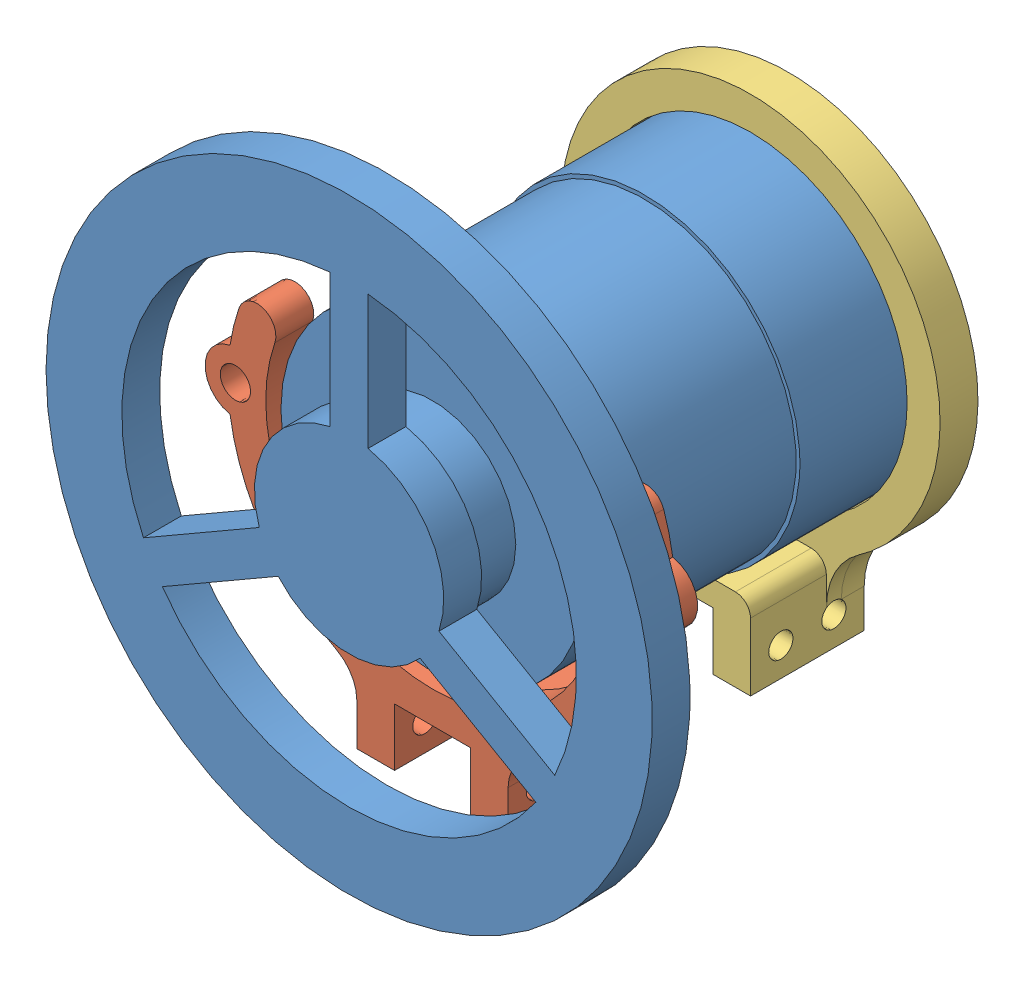
SolidWorks assembly flywheel, configuration 默认. Lengths in mm.
Overall size (80 80 59).
3 component instances, 3 part files, 9 mates.
Components (placement in the parent):
- flywheel-1: flywheel [默认] at origin size (80 80 59)
- flywheel_holder1-1: flywheel_holder1 [默认] at (0 0 48) x (1 0 0) z (0 1 0) size (60 15 44.31)
- flywheel_holder2-1: flywheel_holder2 [默认] at (0 0 1) x (-1 0 0) z (0 1 0) size (50 15 58.81)
Mates (geometry in assembly coordinates):
- 同心1: concentric aligned: circle of flywheel-1; circle of flywheel_holder1-1
- 同心2: concentric aligned: circle of flywheel-1; circle of flywheel_holder2-1
- 重合3: coincident aligned: plane of flywheel-1 through (0 -2.9898 0) normal (0 1 0); plane of flywheel_holder1-1 through (0 -2.9898 48) normal (0 1 0)
- 重合4: coincident aligned: plane of flywheel-1 through (0 -2.9898 0) normal (0 1 0); plane of flywheel_holder2-1 through (0 -2.9898 1) normal (0 1 0)
- 重合5: coincident aligned: plane of flywheel-1 through (0 -2.9898 48) normal (0 0 1); plane of flywheel_holder1-1 through (-11.5785 1.0102 48) normal (0 0 1)
- 距离1: distance = 1 mm aligned: plane of flywheel-1 through (0 0 0) normal (0 0 -1); plane of flywheel_holder2-1 through (0 0 1) normal (0 0 -1)
- 重合6: coincident aligned: plane of flywheel-1 through (0 -2.9898 0) normal (1 0 0)
- 重合7: coincident aligned: plane of flywheel-1 through (0 0 0) normal (0 0 1)
- 重合8: coincident aligned: plane of flywheel-1 through (0 0 0) normal (0 1 0)
